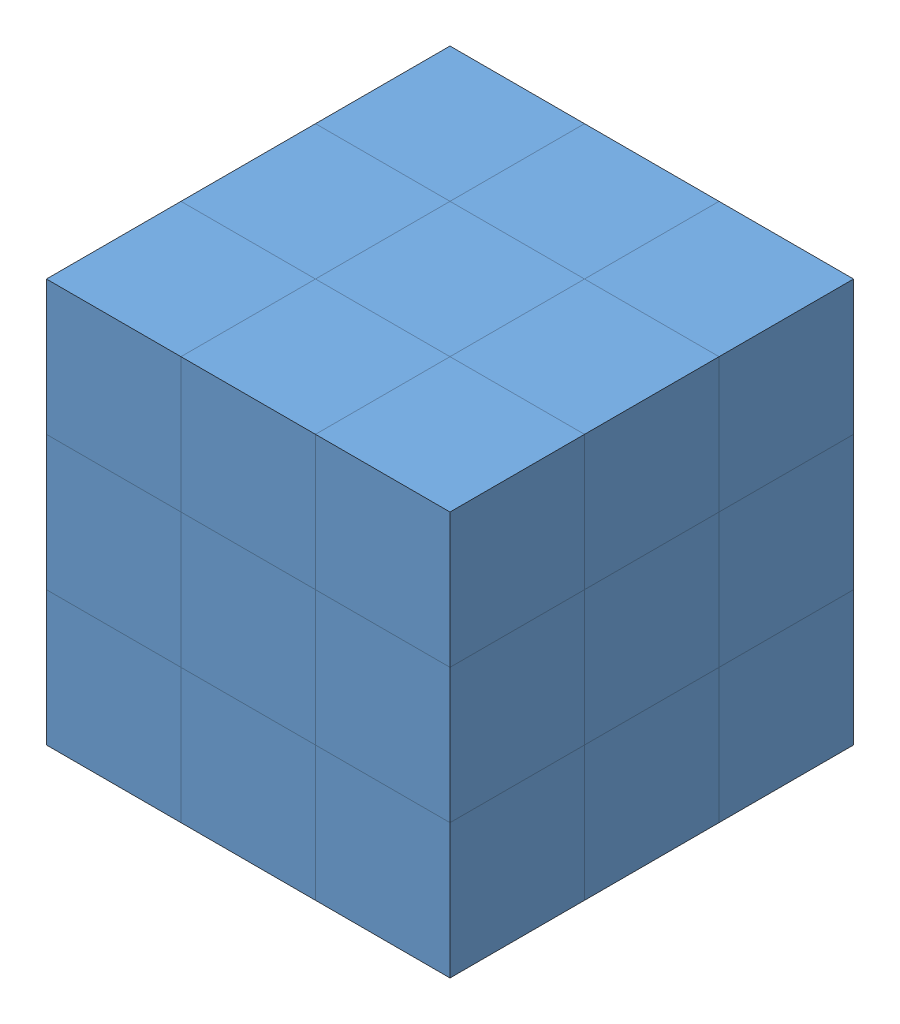
SolidWorks assembly Assem2, configuration Default. Lengths in mm.
Overall size (60 60 60).
32 component instances, 1 part files, 12 mates.
Components (placement in the parent):
- Red Piece-3: Red Piece [Default] at origin size (60 40 60)
  - cube-1: cube [Default] at (30 0 10) size (20 20 20)
  - cube-2: cube [Default] at (30 0 30) size (20 20 20)
  - cube-3: cube [Default] at (50 0 10) size (20 20 20)
  - cube-4: cube [Default] at (10 0 50) size (20 20 20)
  - cube-5: cube [Default] at (10 0 30) size (20 20 20)
  - cube-6: cube [Default] at (10 20 50) size (20 20 20)
- Orange Piece-1: Orange Piece [Default] at (10 20 10) x (-1 0 0) z (0 0 -1) size (40 60 60)
  - cube-1: cube [Default] at origin size (20 20 20)
  - cube-2: cube [Default] at (0 20 0) size (20 20 20)
  - cube-3: cube [Default] at (0 -20 0) size (20 20 20)
  - cube-4: cube [Default] at (0 20 -40) size (20 20 20)
  - cube-5: cube [Default] at (0 20 -20) x (0 0 1) z (-1 0 0) size (20 20 20)
  - cube-6: cube [Default] at (-20 20 -20) size (20 20 20)
- White Piece-1: White Piece [Default] at (50 20 50) x (0 0 1) z (-1 0 0) size (60 20 60)
  - cube-1: cube [Default] at origin size (20 20 20)
  - cube-2: cube [Default] at (-20 0 0) size (20 20 20)
  - cube-3: cube [Default] at (-40 0 0) size (20 20 20)
  - cube-4: cube [Default] at (-20 0 20) size (20 20 20)
  - cube-5: cube [Default] at (-20 0 40) size (20 20 20)
- Blue Piece-1: Blue Piece [Default] at (50 40 50) x (0 0 1) z (-1 0 0) size (40 60 40)
  - cube-1: cube [Default] at origin size (20 20 20)
  - cube-2: cube [Default] at (0 -40 20) size (20 20 20)
  - cube-3: cube [Default] at (0 0 20) size (20 20 20)
  - cube-4: cube [Default] at (0 -20 20) size (20 20 20)
  - cube-5: cube [Default] at (0 -40 0) size (20 20 20)
  - cube-6: cube [Default] at (-20 -40 0) size (20 20 20)
- Yellow Piece-1: Yellow Piece [Default] at (50 40 10) x (0 0 1) z (-1 0 0) size (40 40 40)
  - cube-1: cube [Default] at origin size (20 20 20)
  - cube-3: cube [Default] at (0 0 20) size (20 20 20)
  - cube-4: cube [Default] at (20 0 0) size (20 20 20)
  - cube-5: cube [Default] at (0 -20 20) size (20 20 20)
Mates (geometry in assembly coordinates):
- Coincident11: coincident aligned: plane of Red Piece-3/cube-6 through (20 40 60) normal (0 0 1); plane of Orange Piece-1/cube-4 through (0 60 60) normal (0 0 1)
- Coincident12: coincident anti-aligned: plane of Red Piece-3/cube-6 through (10 40 50) normal (0 1 0); plane of Orange Piece-1/cube-4 through (10 40 50) normal (0 -1 0)
- Coincident13: coincident aligned: plane of Red Piece-3/cube-6 through (0 40 60) normal (-1 0 0); plane of Orange Piece-1/cube-4 through (0 60 40) normal (-1 0 0)
- Coincident15: coincident aligned: plane of Red Piece-3/cube-5 through (0 20 40) normal (-1 0 0); plane of White Piece-1/cube-5 through (0 40 40) normal (-1 0 0)
- Coincident16: coincident aligned: plane of Red Piece-3/cube-3 through (60 20 0) normal (0 0 -1); plane of White Piece-1/cube-3 through (40 40 0) normal (0 0 -1)
- Coincident17: coincident anti-aligned: plane of Orange Piece-1/cube-6 through (30 40 30) normal (0 -1 0); plane of White Piece-1/cube-2 through (50 40 30) normal (0 1 0)
- Coincident18: coincident aligned: plane of White Piece-1/cube-1 through (60 40 60) normal (1 0 0); plane of Blue Piece-1/cube-1 through (60 60 60) normal (1 0 0)
- Coincident19: coincident anti-aligned: plane of White Piece-1/cube-2 through (50 20 30) normal (0 -1 0); plane of Blue Piece-1/cube-6 through (50 20 30) normal (0 1 0)
- Coincident20: coincident aligned: plane of White Piece-1/cube-1 through (40 40 60) normal (0 0 1); plane of Blue Piece-1/cube-5 through (40 20 60) normal (0 0 1)
- Coincident21: coincident: plane of Blue Piece-1/cube-1 through (40 60 40) normal (0 0 -1); plane of Yellow Piece-1/cube-4 through (40 60 40) normal (0 0 1)
- Coincident22: coincident: plane of White Piece-1/cube-3 through (60 40 20) normal (1 0 0); plane of Yellow Piece-1/cube-1 through (60 60 20) normal (1 0 0)
- Coincident23: coincident aligned: plane of Orange Piece-1/cube-6 through (30 60 30) normal (0 1 0); plane of Yellow Piece-1/cube-3 through (30 60 10) normal (0 1 0)
